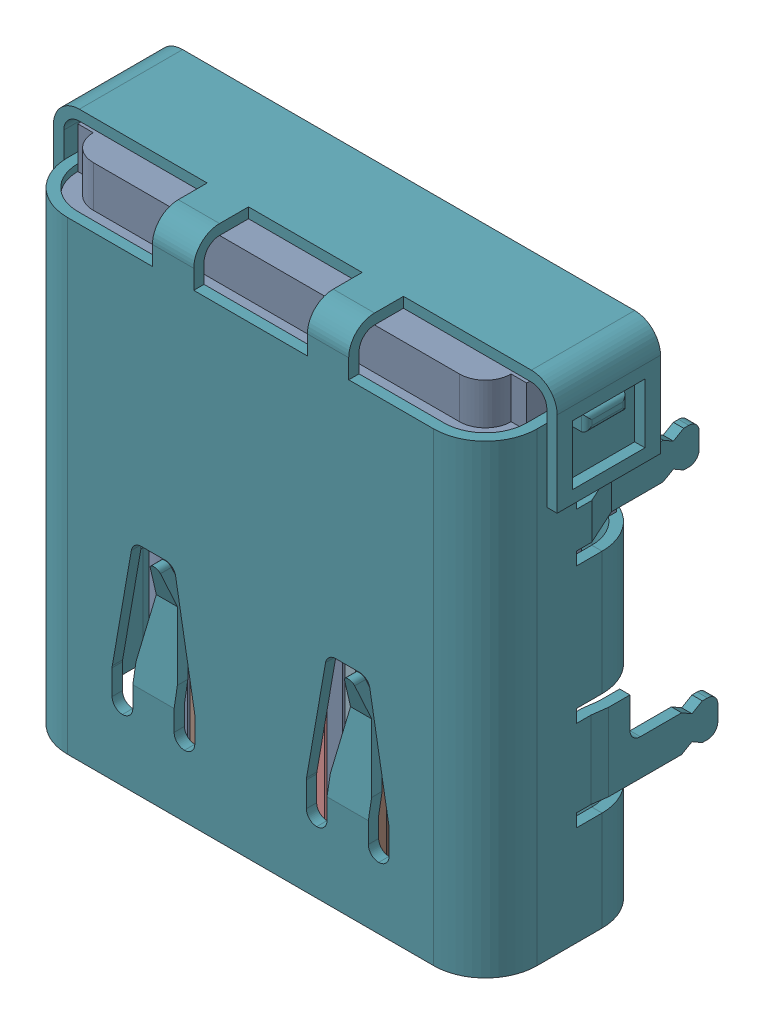
SolidWorks assembly USB3, configuration Défaut. Lengths in mm.
Overall size (9.75 9.87 4.46).
4 component instances, 1 part files, 0 mates.
Components (placement in the parent):
- KH-TYPE-C-24P-T9.87-1: KH-TYPE-C-24P-T9.87 [Défaut] at (46.8 -34.1968 -1.55) x (1 0 0) z (0 0 1) size (9.75 9.87 4.46)
  - 3D_PCB1_2021-12-30.step-1: 3D_PCB1_2021-12-30.step [Défaut] at origin size (9.75 9.87 4.46)
    - e9773ad0a1ba4615a8cdbe787346df90.step-1: e9773ad0a1ba4615a8cdbe787346df90.step [Défaut] at (5.0419 -6.8961 1.6) size (9.75 9.87 4.46)
      - COMPOUND.step_810-1: COMPOUND.step_810 [Défaut] at origin size (9.75 9.87 4.46)
